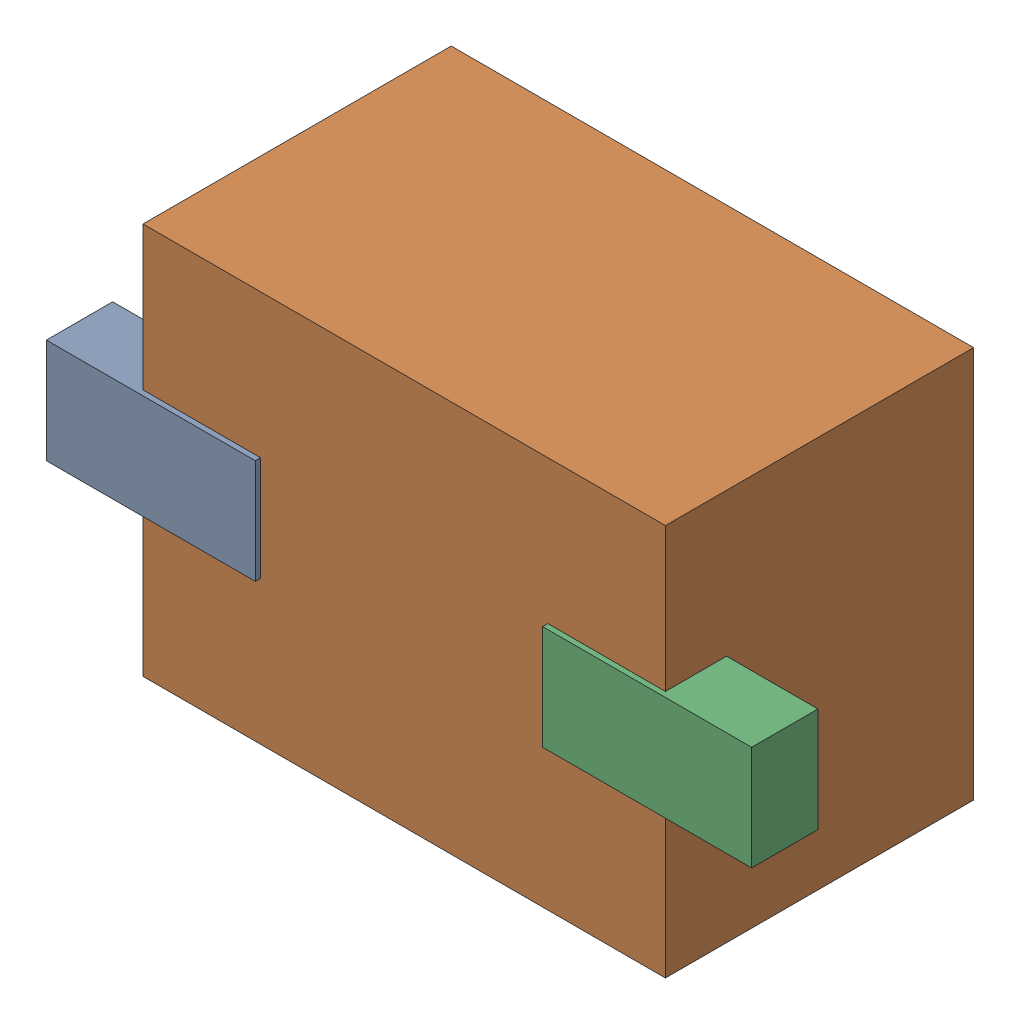
SolidWorks assembly D5, configuration Default. Lengths in mm.
Overall size (2.7 1.5 1.2).
6 component instances, 2 part files, 0 mates.
Components (placement in the parent):
- 710424080_4-1: 710424080_4 [Default] at (9.75 35 -0.6655) size (0.8 0.4 0.25)
  - Extruded (18)-1: Extruded (18) [Default] at origin size (0.8 0.4 0.25)
- 710423952_2-1: 710423952_2 [Default] at (10.7 35 -1.6115) size (2 1.5 1.18)
  - Extruded (19)-1: Extruded (19) [Default] at origin size (2 1.5 1.18)
- 710424080_5-1: 710424080_5 [Default] at (11.65 35 -0.6655) size (0.8 0.4 0.25)
  - Extruded (18)-1: Extruded (18) [Default] at origin size (0.8 0.4 0.25)
